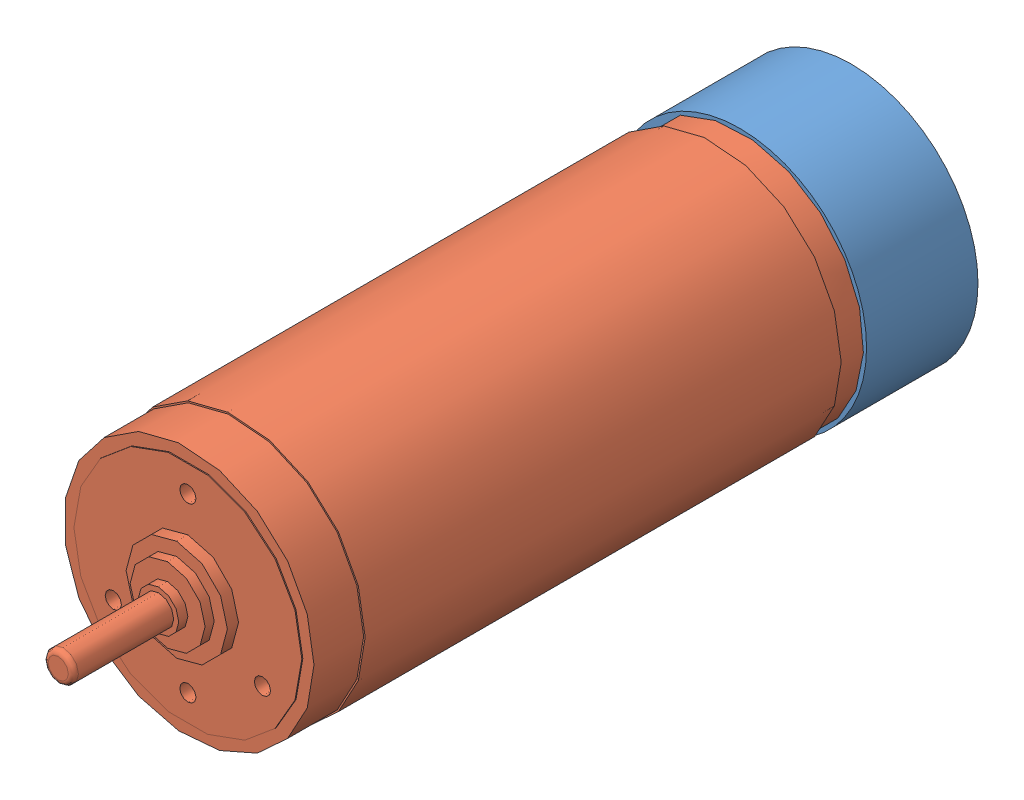
SolidWorks assembly Assem2, configuration Default. Lengths in mm.
Overall size (25 25 83).
5 component instances, 4 part files, 2 mates.
Components (placement in the parent):
- tacho-1: tacho [Default] at (17.158 13.4571 9.2808) size (25 25 11)
- 118752-1: 118752 [Default] at (17.158 13.4571 74.7808) x (0 0 -1) z (1 0 0) size (83 25 25)
  - 118752_01-1: 118752_01 [Default] at origin size (83 25 25)
  - 118752_02-1: 118752_02 [Default] at origin size (10.7 2.26 2.26)
  - 118752_03-1: 118752_03 [Default] at origin size (10.7 2.26 2.26)
Mates (geometry in assembly coordinates):
- Coincident1: coincident anti-aligned: plane of tacho-1 through (17.158 13.4571 20.2808) normal (0 0 1); plane of 118752-1/118752_01-1 through (17.158 13.4571 20.2808) normal (0 0 -1)
- Concentric1: concentric anti-aligned: cylinder of tacho-1 through (17.158 13.4571 20.2808) axis (0 0 -1) radius 12.5; circle of 118752-1/118752_01-1
